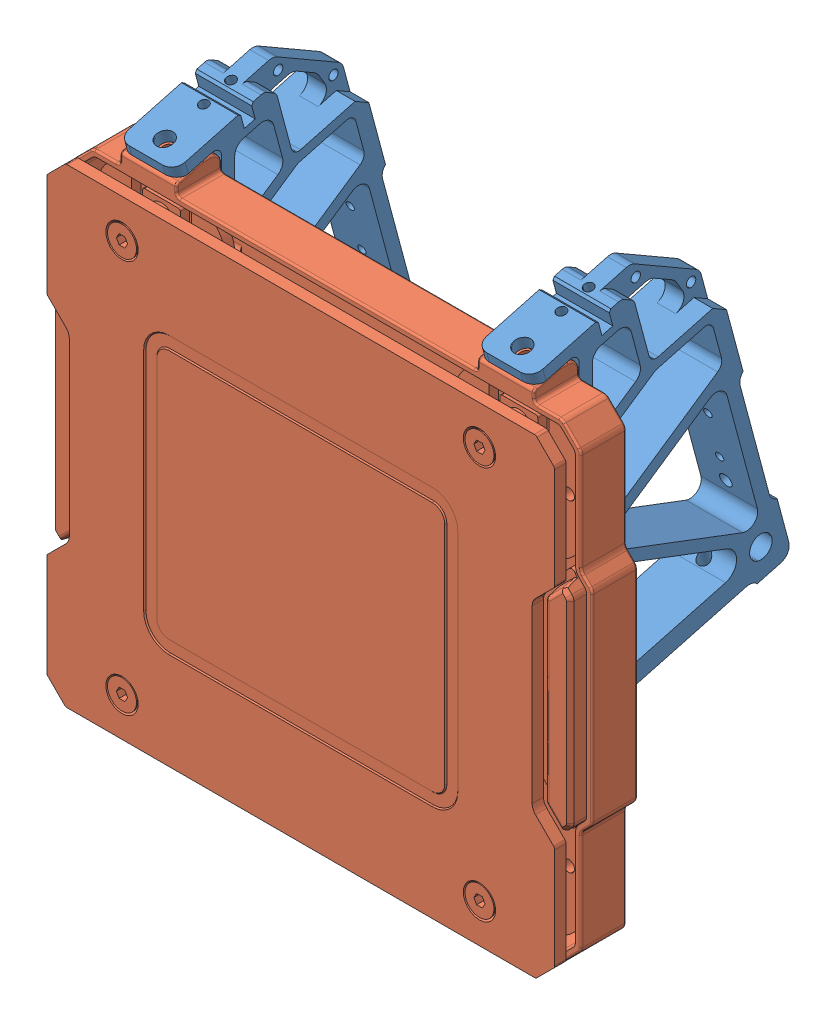
SolidWorks assembly 二版小装甲2.5, configuration 默认. Lengths in mm.
Overall size (141 139.38 74.83).
3 component instances, 2 part files, 25 mates.
Components (placement in the parent):
- 二版RM2019裁判系统支撑架AH022.5-1: 二版RM2019裁判系统支撑架AH022.5 [默认] at (-70.9619 -67.0414 193.9297) size (15 130.97 68.39)
- 二版RM2019裁判系统支撑架AH022.5-2: 二版RM2019裁判系统支撑架AH022.5 [默认] at (24.0381 -67.2149 193.8832) size (15 130.97 68.39)
- 二版RM2019裁判系统装甲模块AM022.5-1: 二版RM2019裁判系统装甲模块AM022.5 [默认] at (-68.4663 -109.8435 220.7902) x (0 0 1) z (-1 0 0) size (19 129.97 141)
Mates (geometry in assembly coordinates):
- 重合1: coincident anti-aligned: plane of 二版RM2019裁判系统支撑架AH022.5-1 through (-28.7798 26.1335 193.9297) normal (0 0.965926 0.258819); plane of ? through (-53.1645 50.7171 130.8702) normal (0 -0.965926 -0.258819)
- 同心1: concentric aligned: cylinder of 二版RM2019裁判系统支撑架AH022.5-1 through (-70.9619 21.0472 189.5806) axis (0 0.965926 0.258819) radius 1.25; cylinder of ? through (-45.6645 38.8769 148.0122) axis (0 0.965926 0.258819) radius 1.5
- 同心2: concentric aligned: cylinder of 二版RM2019裁判系统支撑架AH022.5-1 through (-70.9619 21.9741 182.0644) axis (0 0.965926 0.258819) radius 1.25; cylinder of ? through (-45.6645 40.8181 140.7678) axis (0 0.965926 0.258819) radius 1.5
- 重合4: coincident anti-aligned: plane of 二版RM2019裁判系统支撑架AH022.5-2 through (66.2202 25.9599 193.8832) normal (0 0.965926 0.258819); plane of ? through (41.8355 50.7171 130.8702) normal (0 -0.965926 -0.258819)
- 同心5: concentric aligned: cylinder of 二版RM2019裁判系统支撑架AH022.5-2 through (24.0381 20.8737 189.534) axis (0 0.965926 0.258819) radius 1.25; cylinder of ? through (49.3355 38.8769 148.0122) axis (0 0.965926 0.258819) radius 1.5
- 同心6: concentric aligned: cylinder of 二版RM2019裁判系统支撑架AH022.5-2 through (24.0381 21.8006 182.0178) axis (0 0.965926 0.258819) radius 1.25; cylinder of ? through (49.3355 40.8181 140.7678) axis (0 0.965926 0.258819) radius 1.5
- 同心7: concentric: cylinder of ? through (-45.6645 57.3423 148.0942) axis (0 0.258819 -0.965926) radius 2.25; cylinder of ? through (-45.6645 59.9305 138.435) axis (0 -0.258819 0.965926) radius 1.65
- 重合5: coincident: plane of ? through (-24.0453 53.1691 136.6232) normal (0 0.258819 -0.965926); plane of ? through (-38.1645 53.1541 136.6192) normal (0 -0.258819 0.965926)
- 平行1: parallel: plane of ? through (-53.1645 53.1 136.7428) normal (0 0.866025 0.5); plane of ? through (1.8355 87.5118 77.11) normal (0 -0.866025 -0.5)
- 同心8: concentric: cylinder of ? through (49.3355 59.9305 138.435) axis (0 -0.258819 0.965926) radius 1.65; cylinder of ? through (49.3355 57.3423 148.0942) axis (0 0.258819 -0.965926) radius 2.25
- 重合6: coincident: plane of ? through (-38.1645 53.1541 136.6192) normal (0 -0.258819 0.965926); plane of ? through (70.9547 53.1691 136.6232) normal (0 0.258819 -0.965926)
- 平行2: parallel: plane of ? through (1.8355 87.5118 77.11) normal (0 -0.866025 -0.5); plane of ? through (41.8355 53.1 136.7428) normal (0 0.866025 0.5)
- 重合8: coincident anti-aligned: plane of 二版RM2019裁判系统支撑架AH022.5-2 through (2.4188 22.6471 193.8832) normal (0 -0.965926 -0.258819); plane of ? through (41.8355 41.5809 152.6031) normal (0 0.965926 0.258819)
- 同心9: concentric anti-aligned: cylinder of 二版RM2019裁判系统支撑架AH022.5-2 through (24.0381 30.4925 203.2406) axis (0 -0.965926 -0.258819) radius 2.25; cylinder of ? through (49.3355 39.7651 159.3794) axis (0 0.965926 0.258819) radius 1.65
- 同心10: concentric anti-aligned: cylinder of 二版RM2019裁判系统支撑架AH022.5-1 through (-70.9619 30.6661 203.2871) axis (0 -0.965926 -0.258819) radius 2.25; cylinder of ? through (-45.6645 39.7651 159.3794) axis (0 0.965926 0.258819) radius 1.65
- 同心11: concentric aligned: cylinder of 二版RM2019裁判系统支撑架AH022.5-2 through (24.0381 30.4925 203.2406) axis (0 -0.965926 -0.258819) radius 2.25; circle of 二版RM2019裁判系统装甲模块AM02-1
- 同心12: concentric anti-aligned: cylinder of 二版RM2019裁判系统支撑架AH022.5-1 through (-70.9619 30.6661 203.2871) axis (0 -0.965926 -0.258819) radius 2.25; cylinder of 二版RM2019裁判系统装甲模块AM022.5-1 through (-70.9619 21.0068 200.6989) axis (0 0.965926 0.258819) radius 1.65
- 同心13: concentric aligned: cylinder of 二版RM2019裁判系统支撑架AH022.5-1 through (-70.9619 30.6661 203.2871) axis (0 -0.965926 -0.258819) radius 2.25; cylinder of 螺栓M4-8-2 through (-45.6645 35.1287 158.1371) axis (0 -0.965926 -0.258819) radius 2
- 重合9: coincident anti-aligned: plane of 二版RM2019裁判系统支撑架AH022.5-1 through (-28.7798 26.1335 193.9297) normal (0 0.965926 0.258819); plane of 螺栓M4-8-2 through (-48.8645 42.8561 160.2077) normal (0 -0.965926 -0.258819)
- 同心14: concentric aligned: cylinder of 二版RM2019裁判系统支撑架AH022.5-2 through (24.0381 30.4925 203.2406) axis (0 -0.965926 -0.258819) radius 2.25; cylinder of 螺栓M4-8-1 through (49.3355 35.1287 158.1371) axis (0 -0.965926 -0.258819) radius 2
- 重合10: coincident aligned: plane of 螺栓M4-8-1 through (49.3355 46.5266 161.1912) normal (0 0.965926 0.258819); plane of 螺栓M4-8-2 through (-45.6645 46.5266 161.1912) normal (0 0.965926 0.258819)
- 同心15: concentric anti-aligned: circle of 二版RM2019裁判系统支撑架AH022.5-1; cylinder of 二版RM2019裁判系统装甲模块AM022.5-1 through (-70.9619 21.0068 200.6989) axis (0 0.965926 0.258819) radius 1.65
- 同心16: concentric anti-aligned: cylinder of 二版RM2019裁判系统支撑架AH022.5-2 through (24.0381 30.4925 203.2406) axis (0 -0.965926 -0.258819) radius 2.25; cylinder of 二版RM2019裁判系统装甲模块AM022.5-1 through (24.0381 21.0068 200.6989) axis (0 0.965926 0.258819) radius 1.65
- 重合11: coincident anti-aligned: plane of 二版RM2019裁判系统支撑架AH022.5-2 through (31.5381 22.7851 193.8832) normal (0 0 1); plane of 二版RM2019裁判系统装甲模块AM022.5-1 through (-23.4619 -45.8823 193.8832) normal (0 0 -1)
- 重合13: coincident anti-aligned: plane of 二版RM2019裁判系统支撑架AH022.5-1 through (-92.5812 22.8206 193.9297) normal (0 -0.965926 -0.258819); plane of 二版RM2019裁判系统装甲模块AM022.5-1 through (-63.4619 22.8331 193.8832) normal (0 0.965926 0.258819)
